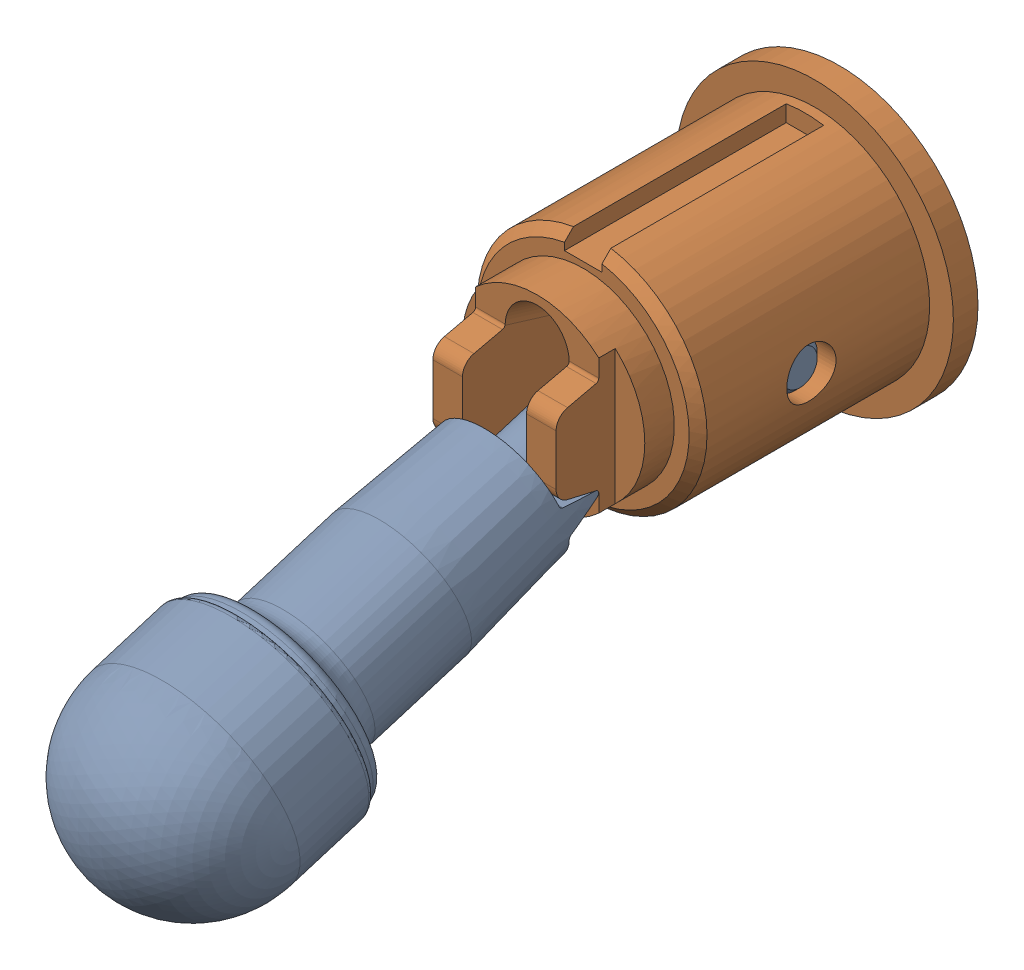
SolidWorks assembly MS Toggle Switch Locking F Ref v3, configuration Default. Lengths in mm.
Overall size (14.29 21.75 40.02).
2 component instances, 2 part files, 0 mates.
Components (placement in the parent):
- Toggle Lever Locking Round Ref-1: Toggle Lever Locking Round Ref [Default] at (-38.1 90.6823 -6.2741) x (-1 0 0) z (0 -0.292372 0.956305) size (10.67 10.67 36.48)
- Toggle Threads Locking Ref-1: Toggle Threads Locking Ref [Default] at (-38.1 88.9 -6.5405) x (-1 0 0) z (0 0 1) size (14.29 14.29 17.92)
